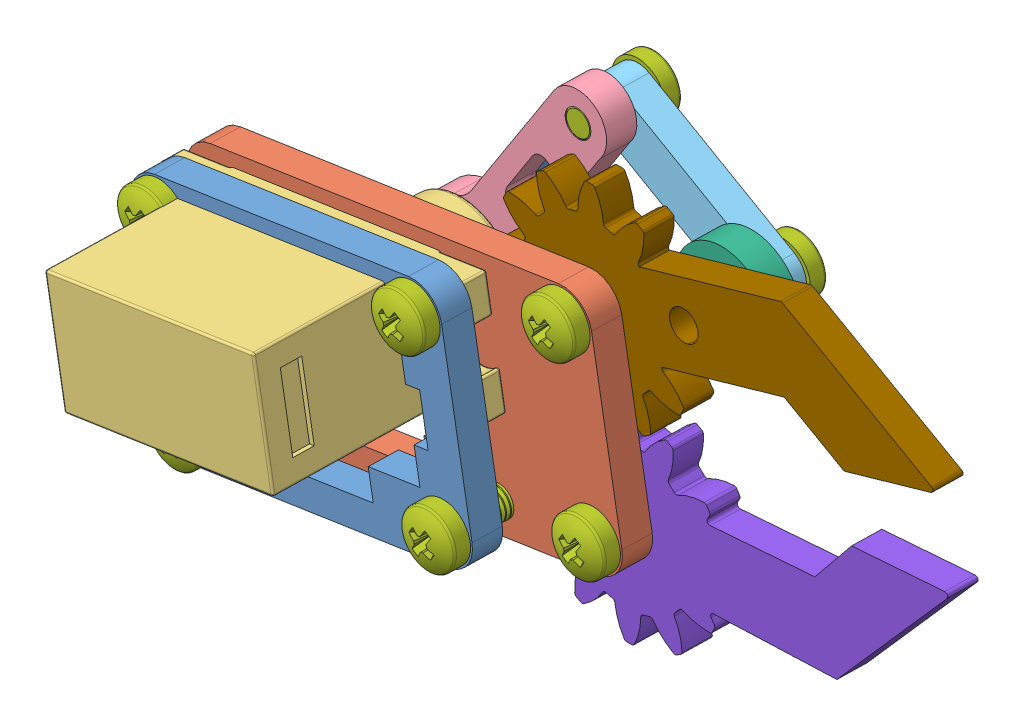
SolidWorks assembly Mecanismo, configuration Défaut. Lengths in mm.
Overall size (80.73 50.11 33.76).
19 component instances, 12 part files, 40 mates.
Components (placement in the parent):
- 21-1: 21 [Défaut] at (157.0398 -18.5763 183.6868) x (-0.984739 -0.171961 -0.026807) z (-0.026408 -0.004611 0.999641) size (33 24 3)
- 22-1: 22 [Défaut] at (170.998 -41.173 178.4149) x (-0.984739 -0.171961 -0.026807) z (-0.026408 -0.004611 0.999641) size (43.02 24 3)
- TowPro-SG90-9g-3: TowPro-SG90-9g [Défaut] at (121.5042 9.079 198.8814) x (-0.984739 -0.171961 -0.026807) z (0.172023 -0.985093 0) size (32.2 27.94 12)
- 5-2: 5 [Défaut] at (113.6146 35.8427 173.3455) x (0.546887 0.837007 0.018309) z (0.026408 0.004611 -0.999641) size (30.47 11 3)
- 3-1: 3 [Défaut] at (130.6136 -18.1257 167.5435) x (0.880844 -0.472936 0.021088) z (-0.026408 -0.004611 0.999641) size (22 4.8 3)
- 2-4: 2 [Défaut] at (135.7013 -13.8192 170.6988) x (0.999651 0.000017 0.026408) z (-0.026408 -0.004611 0.999641) size (10 10 3)
- pan head cross recess screw_bsi-5: pan head cross recess screw_bsi [M3 x 6] at (137.9405 -8.0535 183.0964) x (0.026408 0.004611 -0.999641) z (0.508292 0.861009 0.0174) size (8.35 5.6 5.6)
- pan head cross recess screw_bsi-6: pan head cross recess screw_bsi [M3 x 6] at (134.8441 9.6782 183.0964) x (0.026408 0.004611 -0.999641) z (0.508292 0.861009 0.0174) size (8.35 5.6 5.6)
- pan head cross recess screw_bsi-12: pan head cross recess screw_bsi [ M3 x 8] at (127.9311 -9.8014 188.3603) x (0.026408 0.004611 -0.999641) z (0.508292 0.861009 0.0174) size (10.35 5.6 5.6)
- pan head cross recess screw_bsi-13: pan head cross recess screw_bsi [ M3 x 8] at (124.8346 7.9302 188.3603) x (0.026408 0.004611 -0.999641) z (0.508292 0.861009 0.0174) size (10.35 5.6 5.6)
- pan head cross recess screw_bsi-14: pan head cross recess screw_bsi [ M3 x 8] at (98.2467 3.2873 187.6365) x (0.026408 0.004611 -0.999641) z (0.508292 0.861009 0.0174) size (10.35 5.6 5.6)
- pan head cross recess screw_bsi-16: pan head cross recess screw_bsi [ M3 x 8] at (101.3431 -14.4444 187.6365) x (0.026408 0.004611 -0.999641) z (0.508292 0.861009 0.0174) size (10.35 5.6 5.6)
- pan head cross recess screw_bsi-38: pan head cross recess screw_bsi [M3 x 6] at (129.6182 20.7977 165.2959) x (-0.026408 -0.004611 0.999641) z (-0.999651 0.00014 -0.026407) size (8.35 5.6 5.6)
- pan head cross recess screw_bsi-39: pan head cross recess screw_bsi [ M3 x 8] at (144.7684 12.6634 165.6586) x (-0.026408 -0.004611 0.999641) z (-0.999651 0.00014 -0.026407) size (10.35 5.6 5.6)
- 24-1: 24 [Défaut] at (29.9241 8.7665 174.9185) x (0.971295 0.23637 0.026749) z (0.026408 0.004611 -0.999641) size (45.92 20.73 3)
- 242-1: 242 [Défaut] at (114.305 95.4283 174.5463) x (0.293428 -0.955975 0.003342) z (-0.026408 -0.004611 0.999641) size (20.36 44.65 3)
- A1-1: A1 [Défaut] at (117.4867 2.3881 169.292) x (0.821366 -0.570082 0.019068) z (-0.026408 -0.004611 0.999641) size (7.5 21 5)
- slotted cheese head screw_iso-1: slotted cheese head screw_iso [ISO 1207 - M1.6 x 5 --- 5S] at (117.4946 2.3895 168.9921) x (-0.026408 -0.004611 0.999641) z (-0.999645 0.003607 -0.026391) size (6.11 3 3)
- slotted cheese head screw_jis-1: slotted cheese head screw_jis [JIS B 1101 Slotted cheese head screw M1.6 x 3 --3S] at (122.4571 9.5181 168.3558) x (-0.026408 -0.004611 0.999641) z (-0.999645 0.003607 -0.026391) size (4.11 3 3)
Mates (geometry in assembly coordinates):
- Coïncidente31: coincident aligned: plane of 21-1 through (124.3819 10.8966 185.9611) normal (-0.172023 0.985093 0); plane of 22-1 through (134.3914 12.6445 180.6972) normal (-0.172023 0.985093 0)
- Coaxiale23: concentric aligned: cylinder of 21-1 through (124.898 7.9413 185.9611) axis (0.026408 0.004611 -0.999641) radius 1.5; cylinder of 22-1 through (125.0442 7.9668 180.4287) axis (0.026408 0.004611 -0.999641) radius 1.5
- Coaxiale461: concentric anti-aligned: cylinder of 22-1 through (138.0039 -8.0424 180.6972) axis (0.026408 0.004611 -0.999641) radius 1.5; cylinder of pan head cross recess screw_bsi-5 through (137.2698 -8.1706 208.4872) axis (-0.026408 -0.004611 0.999641) radius 2.8
- Coïncidente461: coincident anti-aligned: plane of 22-1 through (101.5526 -14.4078 179.7049) normal (-0.026408 -0.004611 0.999641); plane of pan head cross recess screw_bsi-5 through (136.7127 -7.2796 180.6666) normal (0.026408 0.004611 -0.999641)
- Coaxiale471: concentric anti-aligned: cylinder of 22-1 through (134.9075 9.6892 180.6972) axis (0.026408 0.004611 -0.999641) radius 1.5; cylinder of pan head cross recess screw_bsi-6 through (134.1734 9.561 208.4872) axis (-0.026408 -0.004611 0.999641) radius 2.8
- Coïncidente471: coincident anti-aligned: plane of 22-1 through (101.5526 -14.4078 179.7049) normal (-0.026408 -0.004611 0.999641); plane of pan head cross recess screw_bsi-6 through (133.6163 10.4521 180.6666) normal (0.026408 0.004611 -0.999641)
- Coaxiale541: concentric anti-aligned: cylinder of 21-1 through (127.9944 -9.7904 185.9611) axis (0.026408 0.004611 -0.999641) radius 1.5; cylinder of pan head cross recess screw_bsi-12 through (127.2603 -9.9186 213.7511) axis (-0.026408 -0.004611 0.999641) radius 2.8
- Coïncidente541: coincident anti-aligned: plane of 21-1 through (124.898 7.9413 185.9611) normal (-0.026408 -0.004611 0.999641); plane of pan head cross recess screw_bsi-12 through (126.7033 -9.0275 185.9305) normal (0.026408 0.004611 -0.999641)
- Coaxiale551: concentric anti-aligned: cylinder of 21-1 through (124.898 7.9413 185.9611) axis (0.026408 0.004611 -0.999641) radius 1.5; cylinder of pan head cross recess screw_bsi-13 through (124.1639 7.8131 213.7511) axis (-0.026408 -0.004611 0.999641) radius 2.8
- Coïncidente551: coincident anti-aligned: plane of 21-1 through (124.898 7.9413 185.9611) normal (-0.026408 -0.004611 0.999641); plane of pan head cross recess screw_bsi-13 through (123.6068 8.7042 185.9305) normal (0.026408 0.004611 -0.999641)
- Coaxiale561: concentric anti-aligned: cylinder of 21-1 through (98.3101 3.2984 185.2373) axis (0.026408 0.004611 -0.999641) radius 1.5; cylinder of pan head cross recess screw_bsi-14 through (97.5759 3.1702 213.0273) axis (-0.026408 -0.004611 0.999641) radius 2.8
- Coïncidente561: coincident anti-aligned: plane of 21-1 through (124.898 7.9413 185.9611) normal (-0.026408 -0.004611 0.999641); plane of pan head cross recess screw_bsi-14 through (97.0189 4.0612 185.2067) normal (0.026408 0.004611 -0.999641)
- Coaxiale581: concentric anti-aligned: cylinder of 21-1 through (101.4065 -14.4333 185.2373) axis (0.026408 0.004611 -0.999641) radius 1.5; cylinder of pan head cross recess screw_bsi-16 through (100.6723 -14.5615 213.0273) axis (-0.026408 -0.004611 0.999641) radius 2.8
- Coïncidente581: coincident anti-aligned: plane of 21-1 through (124.898 7.9413 185.9611) normal (-0.026408 -0.004611 0.999641); plane of pan head cross recess screw_bsi-16 through (100.1153 -13.6705 185.2067) normal (0.026408 0.004611 -0.999641)
- Coïncidente7898: coincident anti-aligned: plane of 21-1 through (102.2578 -7.6863 185.2909) normal (0.984739 0.171961 0.026807); plane of TowPro-SG90-9g-3 through (101.6729 -6.3627 198.2863) normal (-0.984739 -0.171961 -0.026807)
- Coïncidente79065: coincident anti-aligned: plane of TowPro-SG90-9g-3 through (114.7397 0.565 173.2125) normal (0.026408 0.004611 -0.999641); plane of 5-2 through (129.3963 20.759 173.6928) normal (-0.026408 -0.004611 0.999641)
- Coaxiale73946: concentric aligned: cylinder of TowPro-SG90-9g-3 through (117.4471 2.3812 170.7915) axis (-0.026408 -0.004611 0.999641) radius 2.275; cylinder of 5-2 through (117.4603 2.3835 170.2917) axis (-0.026408 -0.004611 0.999641) radius 3.75
- Coaxiale73948: concentric anti-aligned: cylinder of 5-2 through (129.4756 20.7728 170.6939) axis (-0.026408 -0.004611 0.999641) radius 1.35; cylinder of 3-1 through (129.4756 20.7728 170.6939) axis (0.026408 0.004611 -0.999641) radius 1.5
- Coïncidente79068: coincident anti-aligned: plane of 5-2 through (129.4756 20.7728 170.6939) normal (0.026408 0.004611 -0.999641); plane of 3-1 through (129.4756 20.7728 170.6939) normal (-0.026408 -0.004611 0.999641)
- Coïncidente79071: coincident anti-aligned: plane of 21-1 through (124.9772 7.9551 182.9622) normal (0.026408 0.004611 -0.999641); plane of TowPro-SG90-9g-3 through (97.1717 -7.1487 182.158) normal (-0.026408 -0.004611 0.999641)
- Coaxiale739521: concentric aligned: cylinder of 3-1 through (129.4756 20.7728 170.6939) axis (0.026408 0.004611 -0.999641) radius 1.5; cylinder of pan head cross recess screw_bsi-38 through (130.2889 20.9148 139.905) axis (0.026408 0.004611 -0.999641) radius 2.8
- Coïncidente790721: coincident anti-aligned: plane of 3-1 through (129.5548 20.7866 167.695) normal (0.026408 0.004611 -0.999641); plane of pan head cross recess screw_bsi-38 through (129.5548 22.2866 167.7019) normal (-0.026408 -0.004611 0.999641)
- Coaxiale739531: concentric aligned: cylinder of 3-1 through (144.6258 12.6385 171.0566) axis (0.026408 0.004611 -0.999641) radius 1.5; cylinder of pan head cross recess screw_bsi-39 through (145.4391 12.7805 140.2677) axis (0.026408 0.004611 -0.999641) radius 2.8
- Coïncidente790731: coincident anti-aligned: plane of 3-1 through (129.5548 20.7866 167.695) normal (0.026408 0.004611 -0.999641); plane of pan head cross recess screw_bsi-39 through (144.705 14.1523 168.0646) normal (-0.026408 -0.004611 0.999641)
- Coïncidente7907402: coincident anti-aligned: plane of 22-1 through (101.6319 -14.394 176.706) normal (0.026408 0.004611 -0.999641); plane of 24-1 through (29.9241 8.7665 174.9185) normal (-0.026408 -0.004611 0.999641)
- Coaxiale7395432: concentric anti-aligned: cylinder of 22-1 through (138.0039 -8.0424 180.6972) axis (0.026408 0.004611 -0.999641) radius 1.5; cylinder of 24-1 through (138.1624 -8.0148 174.6994) axis (-0.026408 -0.004611 0.999641) radius 1.5
- Coïncidente7907403: coincident anti-aligned: plane of 22-1 through (101.6319 -14.394 176.706) normal (0.026408 0.004611 -0.999641); plane of 242-1 through (114.2258 95.4144 177.5452) normal (-0.026408 -0.004611 0.999641)
- Coaxiale7395433: concentric aligned: cylinder of 22-1 through (134.9075 9.6892 180.6972) axis (0.026408 0.004611 -0.999641) radius 1.5; cylinder of 242-1 through (134.9867 9.7031 177.6983) axis (0.026408 0.004611 -0.999641) radius 1.5
- Coaxiale7395434: concentric aligned: cylinder of 2-4 through (144.5466 12.6246 174.0555) axis (0.026408 0.004611 -0.999641) radius 1.5; cylinder of 242-1 through (144.4434 12.6066 177.9615) axis (0.026408 0.004611 -0.999641) radius 1.5
- Coïncidente7907404: coincident anti-aligned: plane of 3-1 through (129.4756 20.7728 170.6939) normal (-0.026408 -0.004611 0.999641); plane of 2-4 through (144.6258 12.6385 171.0566) normal (0.026408 0.004611 -0.999641)
- Coaxiale7395436: concentric aligned: cylinder of 3-1 through (144.6258 12.6385 171.0566) axis (0.026408 0.004611 -0.999641) radius 1.5; cylinder of 2-4 through (144.5466 12.6246 174.0555) axis (0.026408 0.004611 -0.999641) radius 1.5
- Contr.Engrenages1: gear = 21 : 21 mm: axis of 242-1 through (134.9867 9.7031 177.6983) axis (0.026408 0.004611 -0.999641); axis of 24-1 through (138.1624 -8.0148 174.6994) axis (-0.026408 -0.004611 0.999641)
- Verrouiller1: lock: unknown of 22-1; unknown of 242-1
- Coaxiale7395437: concentric anti-aligned: cylinder of 5-2 through (117.4603 2.3835 170.2917) axis (-0.026408 -0.004611 0.999641) radius 3.75; cylinder of A1-1 through (117.4603 2.3835 170.2917) axis (0.026408 0.004611 -0.999641) radius 3.75
- Coïncidente7907405: coincident anti-aligned: plane of 5-2 through (129.4756 20.7728 170.6939) normal (0.026408 0.004611 -0.999641); plane of A1-1 through (126.0071 14.7071 170.5743) normal (-0.026408 -0.004611 0.999641)
- Coaxiale73954381: concentric aligned: cylinder of A1-1 through (117.4656 2.3844 170.0917) axis (0.026408 0.004611 -0.999641) radius 2; cylinder of slotted cheese head screw_iso-1 through (118.1654 2.5066 143.6013) axis (0.026408 0.004611 -0.999641) radius 0.8
- Coïncidente79074061: coincident anti-aligned: plane of A1-1 through (117.4656 2.3844 170.0917) normal (0.026408 0.004611 -0.999641); plane of slotted cheese head screw_iso-1 through (117.4684 3.1844 170.0955) normal (-0.026408 -0.004611 0.999641)
- Tangent1: tangent anti-aligned: plane of 5-2 through (123.8695 10.1821 170.497) normal (-0.83679 0.547173 -0.019582); cylinder of A1-1 through (124.5804 12.7772 174.3291) axis (0.026408 0.004611 -0.999641) radius 0.75
- Coaxiale739543841: concentric aligned: cylinder of A1-1 through (122.3013 9.4909 174.2537) axis (0.026408 0.004611 -0.999641) radius 0.75; cylinder of slotted cheese head screw_jis-1 through (123.1278 9.6352 142.965) axis (0.026408 0.004611 -0.999641) radius 0.8
- Coïncidente790740621: coincident anti-aligned: plane of A1-1 through (126.0335 14.7118 169.5747) normal (0.026408 0.004611 -0.999641); plane of slotted cheese head screw_jis-1 through (122.4308 10.313 169.4592) normal (-0.026408 -0.004611 0.999641)
